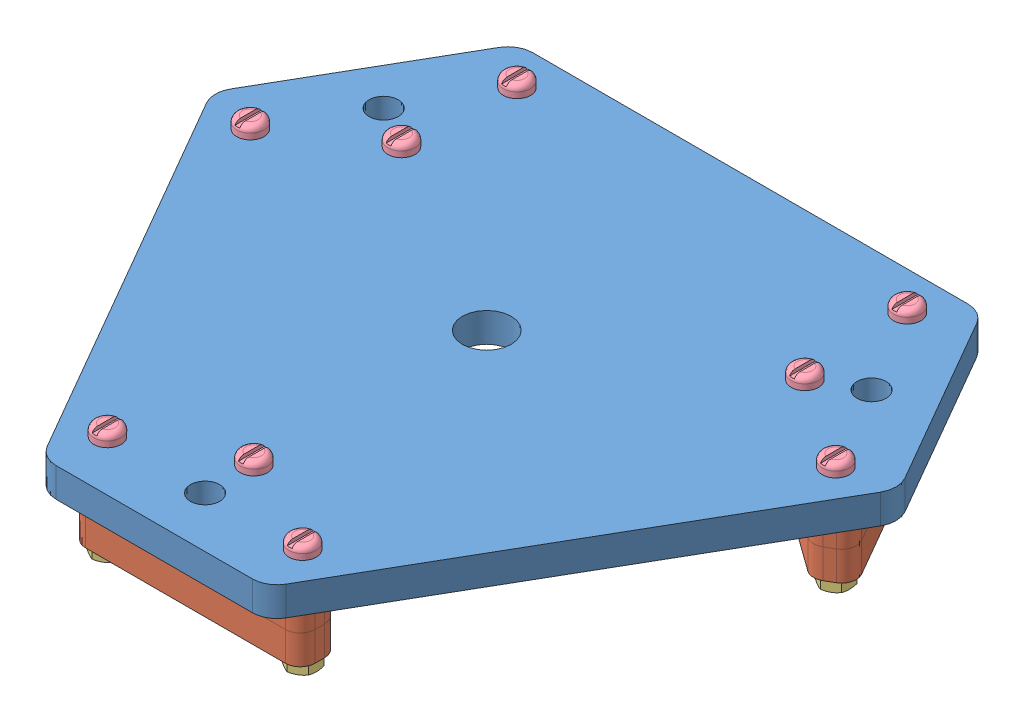
SolidWorks assembly Calibration Block Assembly, configuration Default. Lengths in mm.
Overall size (139.48 22.8 122.14).
25 component instances, 4 part files, 57 mates.
Components (placement in the parent):
- Calibration Plate-1: Calibration Plate [Default] at origin size (139.48 6 122.14)
- Calibration Block-1: Calibration Block [Default] at (53.4641 -6 -30.8675) x (-0.5 0 -0.866025) z (0.866025 0 -0.5) size (47 6 17.21)
- Calibration Block-2: Calibration Block [Default] at (-53.4641 -6 -30.8675) x (-0.5 0 0.866025) z (-0.866025 0 -0.5) size (47 6 17.21)
- Calibration Block-3: Calibration Block [Default] at (0 -6 61.735) size (47 6 17.21)
- Calibration Block-5: Calibration Block [Default] at (0 -12 61.735) size (47 6 17.21)
- Calibration Block-9: Calibration Block [Default] at (53.4641 -12 -30.8675) x (-0.5 0 -0.866025) z (0.866025 0 -0.5) size (47 6 17.21)
- Calibration Block-11: Calibration Block [Default] at (-53.4641 -12 -30.8675) x (-0.5 0 0.866025) z (-0.866025 0 -0.5) size (47 6 17.21)
- hex nut style 1_am-1: hex nut style 1_am [B18.2.4.1M - Hex nut, Style 1,  M3 x 0.5 --D-N] at (20 -14.4 57.735) x (1 0 0) z (0 -1 0) size (5.5 6.35 2.4)
- hex nut style 1_am-2: hex nut style 1_am [B18.2.4.1M - Hex nut, Style 1,  M3 x 0.5 --D-N] at (-20 -14.4 57.735) x (1 0 0) z (0 -1 0) size (5.5 6.35 2.4)
- hex nut style 1_am-3: hex nut style 1_am [B18.2.4.1M - Hex nut, Style 1,  M3 x 0.5 --D-N] at (0 -14.4 47.735) x (1 0 0) z (0 -1 0) size (5.5 6.35 2.4)
- hex nut style 1_am-4: hex nut style 1_am [B18.2.4.1M - Hex nut, Style 1,  M3 x 0.5 --D-N] at (60 -14.4 -11.547) x (1 0 0) z (0 -1 0) size (5.5 6.35 2.4)
- hex nut style 1_am-5: hex nut style 1_am [B18.2.4.1M - Hex nut, Style 1,  M3 x 0.5 --D-N] at (41.3397 -14.4 -23.8675) x (1 0 0) z (0 -1 0) size (5.5 6.35 2.4)
- hex nut style 1_am-6: hex nut style 1_am [B18.2.4.1M - Hex nut, Style 1,  M3 x 0.5 --D-N] at (40 -14.4 -46.188) x (1 0 0) z (0 -1 0) size (5.5 6.35 2.4)
- hex nut style 1_am-7: hex nut style 1_am [B18.2.4.1M - Hex nut, Style 1,  M3 x 0.5 --D-N] at (-41.3397 -14.4 -23.8675) x (1 0 0) z (0 -1 0) size (5.5 6.35 2.4)
- hex nut style 1_am-8: hex nut style 1_am [B18.2.4.1M - Hex nut, Style 1,  M3 x 0.5 --D-N] at (-60 -14.4 -11.547) x (1 0 0) z (0 -1 0) size (5.5 6.35 2.4)
- hex nut style 1_am-9: hex nut style 1_am [B18.2.4.1M - Hex nut, Style 1,  M3 x 0.5 --D-N] at (-40 -14.4 -46.188) x (1 0 0) z (0 -1 0) size (5.5 6.35 2.4)
- pan slot head_am-10: pan slot head_am [B18.6.7M - M3 x 0.5 x 20 Slotted PHMS --20N] at (-60 8.4 -11.547) x (0 -1 0) z (0 0 1) size (22.4 5.6 5.6)
- pan slot head_am-11: pan slot head_am [B18.6.7M - M3 x 0.5 x 20 Slotted PHMS --20N] at (-41.3397 8.4 -23.8675) x (0 -1 0) z (0 0 1) size (22.4 5.6 5.6)
- pan slot head_am-12: pan slot head_am [B18.6.7M - M3 x 0.5 x 20 Slotted PHMS --20N] at (-40 8.4 -46.188) x (0 -1 0) z (0 0 1) size (22.4 5.6 5.6)
- pan slot head_am-13: pan slot head_am [B18.6.7M - M3 x 0.5 x 20 Slotted PHMS --20N] at (40 8.4 -46.188) x (0 -1 0) z (0 0 1) size (22.4 5.6 5.6)
- pan slot head_am-14: pan slot head_am [B18.6.7M - M3 x 0.5 x 20 Slotted PHMS --20N] at (41.3397 8.4 -23.8675) x (0 -1 0) z (0 0 1) size (22.4 5.6 5.6)
- pan slot head_am-15: pan slot head_am [B18.6.7M - M3 x 0.5 x 20 Slotted PHMS --20N] at (60 8.4 -11.547) x (0 -1 0) z (0 0 1) size (22.4 5.6 5.6)
- pan slot head_am-16: pan slot head_am [B18.6.7M - M3 x 0.5 x 20 Slotted PHMS --20N] at (20 8.4 57.735) x (0 -1 0) z (0 0 1) size (22.4 5.6 5.6)
- pan slot head_am-17: pan slot head_am [B18.6.7M - M3 x 0.5 x 20 Slotted PHMS --20N] at (0 8.4 47.735) x (0 -1 0) z (0 0 1) size (22.4 5.6 5.6)
- pan slot head_am-18: pan slot head_am [B18.6.7M - M3 x 0.5 x 20 Slotted PHMS --20N] at (-20 8.4 57.735) x (0 -1 0) z (0 0 1) size (22.4 5.6 5.6)
Mates (geometry in assembly coordinates):
- Coincident1: coincident: plane of Calibration Plate-1 through (0 0 0) normal (0 0 1); plane of assembly through (0 0 0) normal (0 0 1)
- Coincident2: coincident: plane of Calibration Plate-1 through (0 0 0) normal (0 1 0); plane of assembly through (0 0 0) normal (0 1 0)
- Coincident3: coincident aligned: plane of Calibration Plate-1 through (0 0 0) normal (1 0 0); plane of assembly through (0 0 0) normal (1 0 0)
- Parallel1: parallel aligned: plane of Calibration Plate-1 through (47.5 6 -54) normal (0.866025 0 -0.5); plane of Calibration Block-1 through (41.7141 0 -51.2191) normal (0.866025 0 -0.5)
- Coincident5: coincident anti-aligned: plane of Calibration Plate-1 through (0 0 0) normal (0 -1 0); plane of Calibration Block-1 through (53.4641 0 -30.8675) normal (0 1 0)
- Concentric1: concentric anti-aligned: cylinder of Calibration Plate-1 through (50 0 -28.8675) axis (0 1 0) radius 3; cylinder of Calibration Block-1 through (50 0 -28.8675) axis (0 -1 0) radius 3
- Parallel2: parallel aligned: plane of Calibration Plate-1 through (-70.5154 6 -14.1362) normal (-0.866025 0 -0.5); plane of Calibration Block-2 through (-65.2141 0 -10.5159) normal (-0.866025 0 -0.5)
- Coincident6: coincident anti-aligned: plane of Calibration Plate-1 through (0 0 0) normal (0 -1 0); plane of Calibration Block-2 through (-53.4641 0 -30.8675) normal (0 1 0)
- Concentric2: concentric anti-aligned: cylinder of Calibration Plate-1 through (-50 0 -28.8675) axis (0 1 0) radius 3; cylinder of Calibration Block-2 through (-50 0 -28.8675) axis (0 -1 0) radius 3
- Coincident7: coincident anti-aligned: plane of Calibration Plate-1 through (0 0 0) normal (0 -1 0); plane of Calibration Block-3 through (0 0 61.735) normal (0 1 0)
- Parallel3: parallel aligned: plane of Calibration Plate-1 through (23.0154 6 68.1362) normal (0 0 1); plane of Calibration Block-3 through (23.5 0 61.735) normal (0 0 1)
- Concentric4: concentric anti-aligned: cylinder of Calibration Plate-1 through (0 0 57.735) axis (0 1 0) radius 3; cylinder of Calibration Block-3 through (0 0 57.735) axis (0 -1 0) radius 3
- Coincident9: coincident anti-aligned: plane of Calibration Block-3 through (0 -6 61.735) normal (0 -1 0); plane of Calibration Block-5 through (0 -6 61.735) normal (0 1 0)
- Parallel4: parallel aligned: plane of Calibration Plate-1 through (23.0154 6 68.1362) normal (0 0 1); plane of Calibration Block-5 through (23.5 -6 61.735) normal (0 0 1)
- Concentric5: concentric anti-aligned: cylinder of Calibration Plate-1 through (0 0 57.735) axis (0 1 0) radius 3; cylinder of Calibration Block-5 through (0 -6 57.735) axis (0 -1 0) radius 3
- Coincident11: coincident anti-aligned: plane of Calibration Block-1 through (53.4641 -6 -30.8675) normal (0 -1 0); plane of Calibration Block-9 through (53.4641 -6 -30.8675) normal (0 1 0)
- Parallel6: parallel aligned: plane of Calibration Plate-1 through (47.5 6 -54) normal (0.866025 0 -0.5); plane of Calibration Block-9 through (41.7141 -6 -51.2191) normal (0.866025 0 -0.5)
- Concentric7: concentric aligned: cylinder of Calibration Block-1 through (50 0 -28.8675) axis (0 -1 0) radius 3; cylinder of Calibration Block-9 through (50 -6 -28.8675) axis (0 -1 0) radius 3
- Coincident12: coincident anti-aligned: plane of Calibration Block-2 through (-53.4641 -6 -30.8675) normal (0 -1 0); plane of Calibration Block-11 through (-53.4641 -6 -30.8675) normal (0 1 0)
- Parallel7: parallel aligned: plane of Calibration Plate-1 through (-70.5154 6 -14.1362) normal (-0.866025 0 -0.5); plane of Calibration Block-11 through (-65.2141 -6 -10.5159) normal (-0.866025 0 -0.5)
- Concentric8: concentric aligned: cylinder of Calibration Block-2 through (-50 0 -28.8675) axis (0 -1 0) radius 3; cylinder of Calibration Block-11 through (-50 -6 -28.8675) axis (0 -1 0) radius 3
- Concentric18: concentric aligned: cylinder of Calibration Block-5 through (20 -6 57.735) axis (0 -1 0) radius 1.5; cylinder of hex nut style 1_am-1 through (20 10.6375 57.735) axis (0 -1 0) radius 1.5
- Coincident22: coincident anti-aligned: plane of Calibration Block-5 through (0 -12 61.735) normal (0 -1 0); plane of hex nut style 1_am-1 through (20 -12 60.9105) normal (0 1 0)
- Concentric19: concentric aligned: cylinder of Calibration Block-5 through (-20 -6 57.735) axis (0 -1 0) radius 1.5; cylinder of hex nut style 1_am-2 through (-20 10.6375 57.735) axis (0 -1 0) radius 1.5
- Coincident23: coincident anti-aligned: plane of Calibration Block-5 through (0 -12 61.735) normal (0 -1 0); plane of hex nut style 1_am-2 through (-20 -12 60.9105) normal (0 1 0)
- Concentric20: concentric aligned: cylinder of Calibration Block-5 through (0 -6 47.735) axis (0 -1 0) radius 1.5; cylinder of hex nut style 1_am-3 through (0 10.6375 47.735) axis (0 -1 0) radius 1.5
- Coincident24: coincident anti-aligned: plane of Calibration Block-5 through (0 -12 61.735) normal (0 -1 0); plane of hex nut style 1_am-3 through (0 -12 50.9105) normal (0 1 0)
- Concentric21: concentric aligned: cylinder of Calibration Block-9 through (60 -6 -11.547) axis (0 -1 0) radius 1.5; cylinder of hex nut style 1_am-4 through (60 10.6375 -11.547) axis (0 -1 0) radius 1.5
- Coincident25: coincident anti-aligned: plane of Calibration Block-9 through (53.4641 -12 -30.8675) normal (0 -1 0); plane of hex nut style 1_am-4 through (60 -12 -8.3716) normal (0 1 0)
- Concentric22: concentric aligned: cylinder of Calibration Block-9 through (41.3397 -6 -23.8675) axis (0 -1 0) radius 1.5; cylinder of hex nut style 1_am-5 through (41.3397 10.6375 -23.8675) axis (0 -1 0) radius 1.5
- Coincident26: coincident anti-aligned: plane of Calibration Block-9 through (53.4641 -12 -30.8675) normal (0 -1 0); plane of hex nut style 1_am-5 through (41.3397 -12 -20.6921) normal (0 1 0)
- Concentric23: concentric aligned: cylinder of Calibration Block-9 through (40 -6 -46.188) axis (0 -1 0) radius 1.5; cylinder of hex nut style 1_am-6 through (40 10.6375 -46.188) axis (0 -1 0) radius 1.5
- Coincident27: coincident anti-aligned: plane of Calibration Block-9 through (53.4641 -12 -30.8675) normal (0 -1 0); plane of hex nut style 1_am-6 through (40 -12 -43.0126) normal (0 1 0)
- Concentric24: concentric aligned: cylinder of Calibration Block-11 through (-41.3397 -6 -23.8675) axis (0 -1 0) radius 1.5; cylinder of hex nut style 1_am-7 through (-41.3397 10.6375 -23.8675) axis (0 -1 0) radius 1.5
- Coincident28: coincident anti-aligned: plane of Calibration Block-11 through (-53.4641 -12 -30.8675) normal (0 -1 0); plane of hex nut style 1_am-7 through (-41.3397 -12 -20.6921) normal (0 1 0)
- Concentric25: concentric aligned: cylinder of Calibration Block-11 through (-60 -6 -11.547) axis (0 -1 0) radius 1.5; cylinder of hex nut style 1_am-8 through (-60 10.6375 -11.547) axis (0 -1 0) radius 1.5
- Coincident29: coincident anti-aligned: plane of Calibration Block-11 through (-53.4641 -12 -30.8675) normal (0 -1 0); plane of hex nut style 1_am-8 through (-60 -12 -8.3716) normal (0 1 0)
- Concentric26: concentric aligned: cylinder of Calibration Block-11 through (-40 -6 -46.188) axis (0 -1 0) radius 1.5; cylinder of hex nut style 1_am-9 through (-40 10.6375 -46.188) axis (0 -1 0) radius 1.5
- Coincident30: coincident anti-aligned: plane of Calibration Block-11 through (-53.4641 -12 -30.8675) normal (0 -1 0); plane of hex nut style 1_am-9 through (-40 -12 -43.0126) normal (0 1 0)
- Concentric27: concentric aligned: cylinder of Calibration Plate-1 through (-60 0 -11.547) axis (0 1 0) radius 1.5; cylinder of pan slot head_am-10 through (-60 33.8 -11.547) axis (0 1 0) radius 2.8
- Coincident31: coincident anti-aligned: plane of Calibration Plate-1 through (0 6 0) normal (0 1 0); plane of pan slot head_am-10 through (-58.5 6 -11.547) normal (0 -1 0)
- Concentric28: concentric aligned: cylinder of Calibration Plate-1 through (-41.3397 0 -23.8675) axis (0 1 0) radius 1.5; cylinder of pan slot head_am-11 through (-41.3397 33.8 -23.8675) axis (0 1 0) radius 2.8
- Coincident32: coincident anti-aligned: plane of Calibration Plate-1 through (0 6 0) normal (0 1 0); plane of pan slot head_am-11 through (-39.8397 6 -23.8675) normal (0 -1 0)
- Concentric29: concentric aligned: cylinder of Calibration Plate-1 through (-40 0 -46.188) axis (0 1 0) radius 1.5; cylinder of pan slot head_am-12 through (-40 33.8 -46.188) axis (0 1 0) radius 2.8
- Coincident33: coincident anti-aligned: plane of Calibration Plate-1 through (0 6 0) normal (0 1 0); plane of pan slot head_am-12 through (-38.5 6 -46.188) normal (0 -1 0)
- Concentric30: concentric aligned: cylinder of Calibration Plate-1 through (40 0 -46.188) axis (0 1 0) radius 1.5; cylinder of pan slot head_am-13 through (40 33.8 -46.188) axis (0 1 0) radius 2.8
- Coincident34: coincident anti-aligned: plane of Calibration Plate-1 through (0 6 0) normal (0 1 0); plane of pan slot head_am-13 through (41.5 6 -46.188) normal (0 -1 0)
- Concentric31: concentric aligned: cylinder of Calibration Plate-1 through (41.3397 0 -23.8675) axis (0 1 0) radius 1.5; cylinder of pan slot head_am-14 through (41.3397 33.8 -23.8675) axis (0 1 0) radius 2.8
- Coincident35: coincident anti-aligned: plane of Calibration Plate-1 through (0 6 0) normal (0 1 0); plane of pan slot head_am-14 through (42.8397 6 -23.8675) normal (0 -1 0)
- Concentric32: concentric aligned: cylinder of Calibration Plate-1 through (60 0 -11.547) axis (0 1 0) radius 1.5; cylinder of pan slot head_am-15 through (60 33.8 -11.547) axis (0 1 0) radius 2.8
- Coincident36: coincident anti-aligned: plane of Calibration Plate-1 through (0 6 0) normal (0 1 0); plane of pan slot head_am-15 through (61.5 6 -11.547) normal (0 -1 0)
- Concentric33: concentric aligned: cylinder of Calibration Plate-1 through (20 0 57.735) axis (0 1 0) radius 1.5; cylinder of pan slot head_am-16 through (20 33.8 57.735) axis (0 1 0) radius 2.8
- Coincident37: coincident anti-aligned: plane of Calibration Plate-1 through (0 6 0) normal (0 1 0); plane of pan slot head_am-16 through (21.5 6 57.735) normal (0 -1 0)
- Concentric34: concentric aligned: cylinder of Calibration Plate-1 through (0 0 47.735) axis (0 1 0) radius 1.5; cylinder of pan slot head_am-17 through (0 33.8 47.735) axis (0 1 0) radius 2.8
- Coincident38: coincident anti-aligned: plane of Calibration Plate-1 through (0 6 0) normal (0 1 0); plane of pan slot head_am-17 through (1.5 6 47.735) normal (0 -1 0)
- Concentric35: concentric aligned: cylinder of Calibration Plate-1 through (-20 0 57.735) axis (0 1 0) radius 1.5; cylinder of pan slot head_am-18 through (-20 33.8 57.735) axis (0 1 0) radius 2.8
- Coincident39: coincident anti-aligned: plane of Calibration Plate-1 through (0 6 0) normal (0 1 0); plane of pan slot head_am-18 through (-18.5 6 57.735) normal (0 -1 0)
